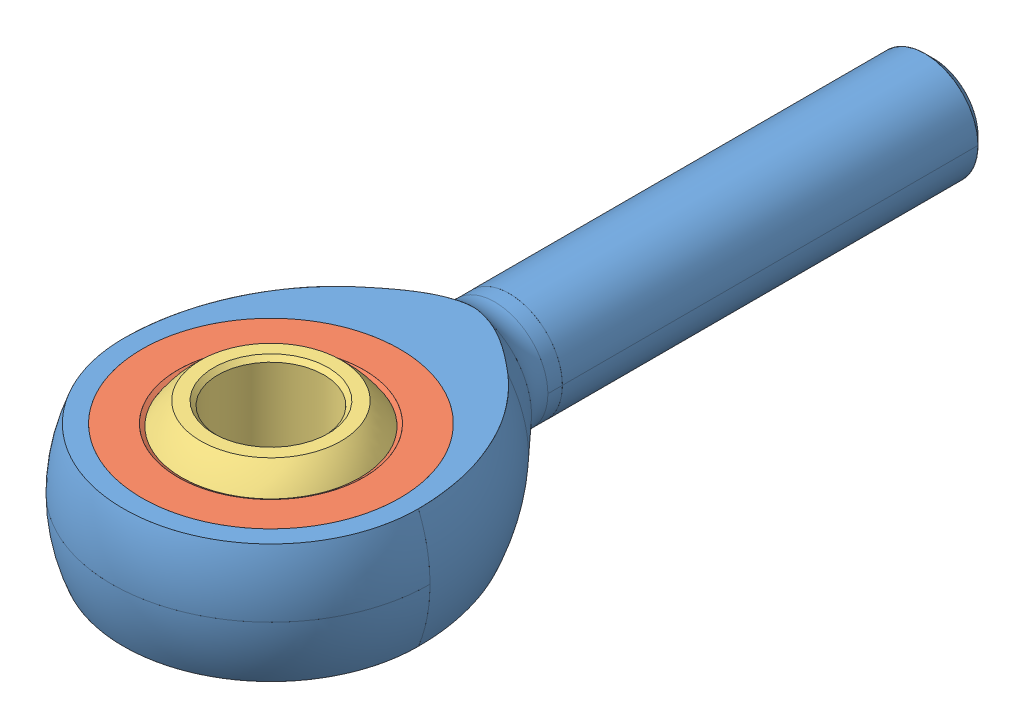
SolidWorks assembly MM-4T, configuration Default. Lengths in mm.
Overall size (22.24 20.31 52.19).
3 component instances, 3 part files, 5 mates.
Components (placement in the parent):
- MM-4T Rod End Body-1: MM-4T Rod End Body [Default] at (0 0 -39.6748) size (22.24 20.31 52.19)
- MM-4T Bearing Bore-1: MM-4T Bearing Bore [Default] at (0 0 -39.6748) size (15.44 7.14 15.44)
- MM-4T Ball Bearing-1: MM-4T Ball Bearing [Default] at (0 0 -39.6748) size (17.9 17.7 16.29)
Mates (geometry in assembly coordinates):
- Coincident6: coordinate: point of MM-4T Rod End body-1
- Concentric1: concentric anti-aligned: cylinder of MM-4T Rod End Body-1 through (0 0 0) axis (0 -1 0) radius 7.3406; cylinder of MM-4T Bearing Bore-1 through (0 0 0) axis (0 1 0) radius 7.3406
- Width1: width aligned: plane of MM-4T Bearing Bore-1 through (0 -3.5687 0) normal (0 -1 0); plane of MM-4T Rod End Body-1 through (0 3.5687 0) normal (0 1 0); plane of MM-4T Bearing Bore-1 through (-9.525 3.5687 0) normal (0 -1 0); plane of MM-4T Rod End Body-1 through (9.525 -3.5687 0) normal (0 1 0)
- Concentric2: concentric anti-aligned: cylinder of MM-4T Rod End Body-1 through (0 0 0) axis (0 -1 0) radius 7.3406; cylinder of MM-4T Ball Bearing-1 through (0 4.7625 0) axis (0 1 0) radius 3.175
- Width2: width anti-aligned: plane of MM-4T Ball Bearing-1 through (0 -4.7625 0) normal (0 -1 0); plane of MM-4T Bearing Bore-1 through (0 4.7625 0) normal (0 1 0); plane of MM-4T Ball Bearing-1 through (0 3.5687 0) normal (0 1 0); plane of MM-4T Bearing Bore-1 through (0 -3.5687 0) normal (0 -1 0)
